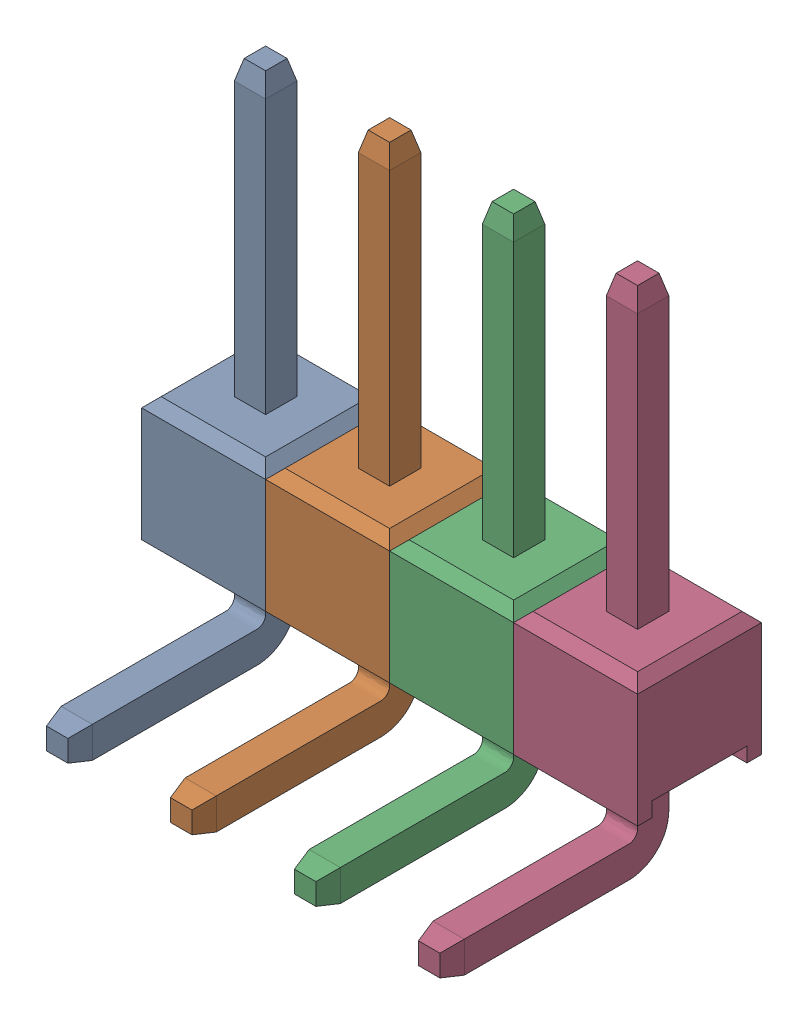
SolidWorks assembly User Library-BluePill_User_Library-header90-4, configuration Default. Lengths in mm.
Overall size (10.16 10.41 5.54).
4 component instances, 1 part files, 0 mates.
Components (placement in the parent):
- User Library-BluePill_User_Library-header90-4_Header90-1-1: User Library-BluePill_User_Library-header90-4_Header90-1 [Default] at (-10.1293 -8.5207 8.231) size (2.54 10.41 5.54)
- User Library-BluePill_User_Library-header90-4_Header90-1-2: User Library-BluePill_User_Library-header90-4_Header90-1 [Default] at (-7.5893 -8.5207 8.231) size (2.54 10.41 5.54)
- User Library-BluePill_User_Library-header90-4_Header90-1-3: User Library-BluePill_User_Library-header90-4_Header90-1 [Default] at (-5.0493 -8.5207 8.231) size (2.54 10.41 5.54)
- User Library-BluePill_User_Library-header90-4_Header90-1-4: User Library-BluePill_User_Library-header90-4_Header90-1 [Default] at (-2.5093 -8.5207 8.231) size (2.54 10.41 5.54)
